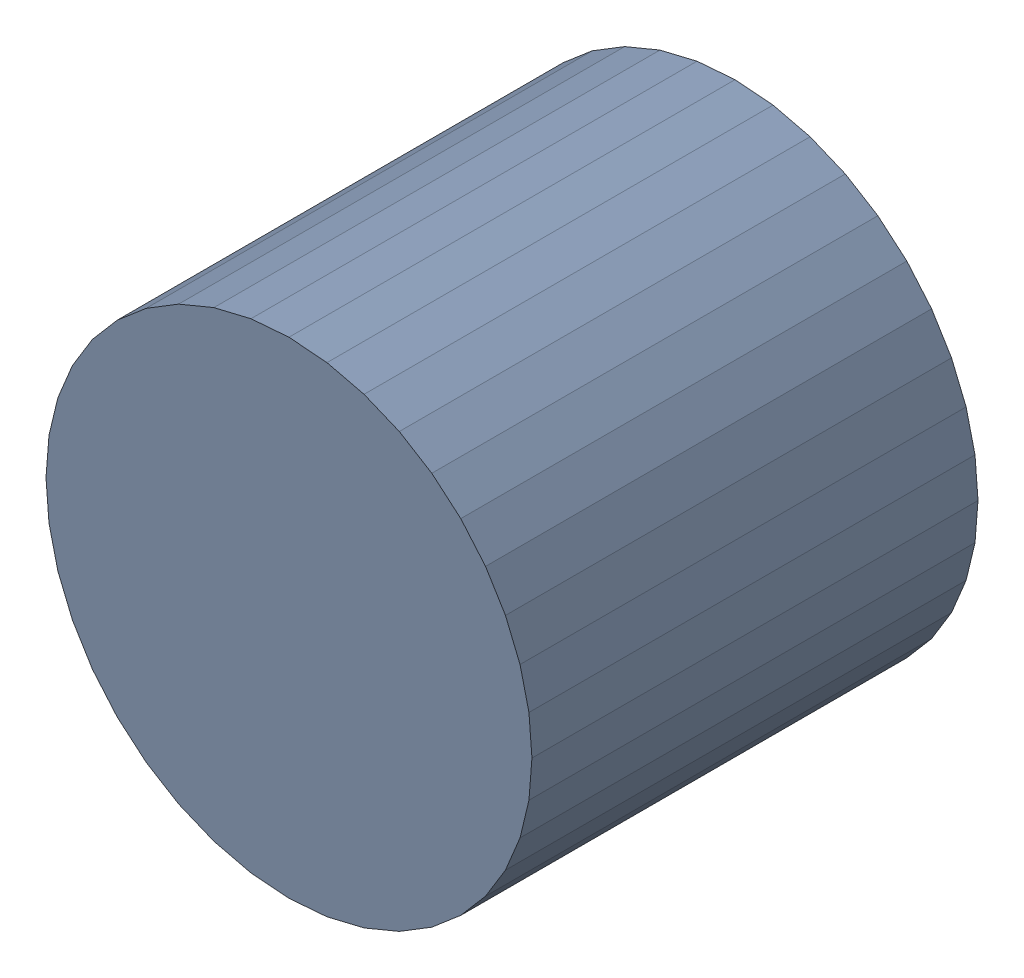
SolidWorks assembly C10_Motor_11Kanaloa_v2.0.0_Motor, configuration Default. Lengths in mm.
Overall size (6.32 6.32 5.8).
2 component instances, 1 part files, 0 mates.
Components (placement in the parent):
- 352892112-1: 352892112 [Default] at (131.572 155.194 0) size (6.32 6.32 5.8)
  - Extruded_11-1: Extruded_11 [Default] at origin size (6.32 6.32 5.8)
